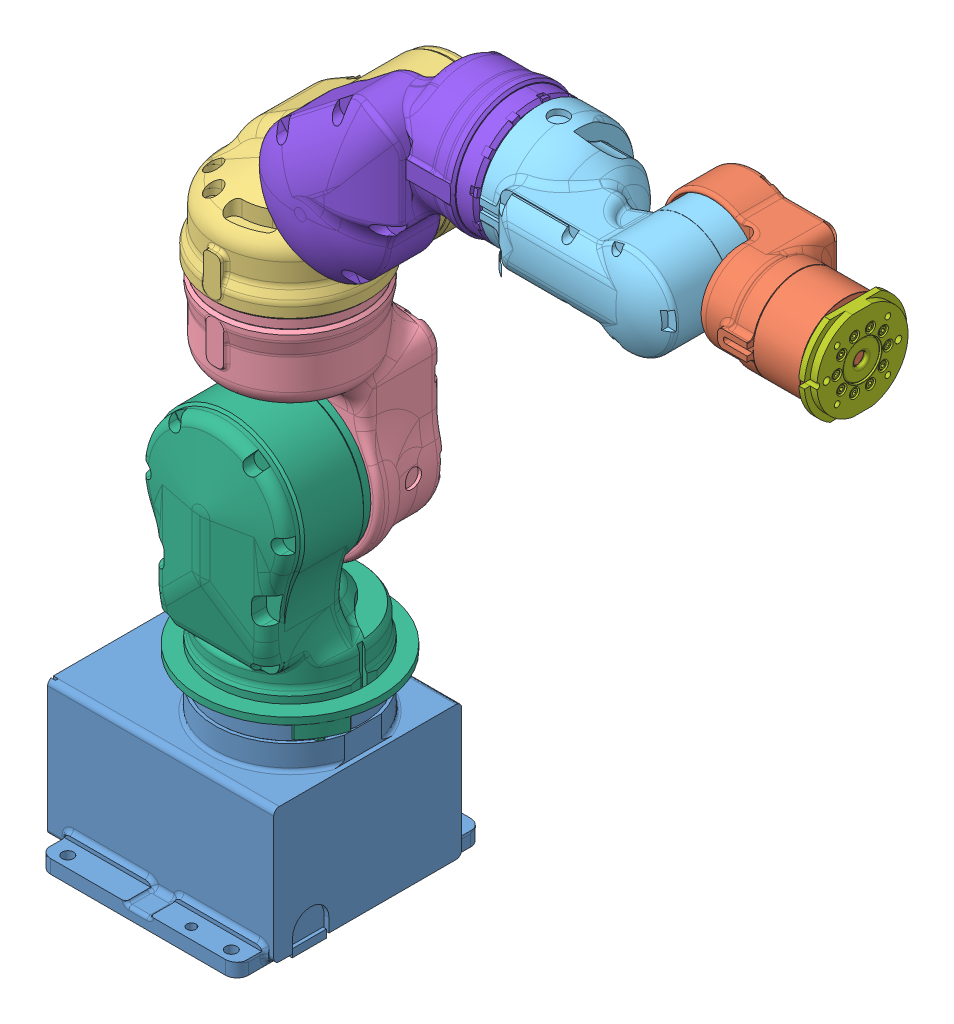
SolidWorks assembly SIA5, configuration ﾃﾞﾌｫﾙﾄ. Lengths in mm.
Overall size (649.6 695.94 220.28).
8 component instances, 8 part files, 16 mates.
Components (placement in the parent):
- base_link-1: base_link [ﾃﾞﾌｫﾙﾄ] at (7.849 -82.5515 222.6419) size (215.3 168.54 220.28)
- link_b-1: link_b [ﾃﾞﾌｫﾙﾄ] at (7.849 -82.5515 222.6419) size (184.27 91.84 114.81)
- link_e-1: link_e [ﾃﾞﾌｫﾙﾄ] at (7.849 -82.5515 222.6419) size (210.08 168.26 150.76)
- link_l-1: link_l [ﾃﾞﾌｫﾙﾄ] at (7.849 -82.5515 222.6419) size (157.25 229.06 145.97)
- link_r-1: link_r [ﾃﾞﾌｫﾙﾄ] at (7.849 -82.5515 222.6419) size (176 105.65 121.5)
- link_s-1: link_s [ﾃﾞﾌｫﾙﾄ] at (7.849 -82.5515 222.6419) size (160 226 160)
- link_t-1: link_t [ﾃﾞﾌｫﾙﾄ] at (7.349 -82.5515 222.6419) size (11 78 89.93)
- link_u-1: link_u [ﾃﾞﾌｫﾙﾄ] at (7.849 -82.5515 222.6419) size (192.08 173.27 131.93)
Mates (geometry in assembly coordinates):
- 一致3: coincident anti-aligned: plane of base_link-1 through (7.849 84.9485 222.6419) normal (0 1 0); plane of link_s-1 through (7.849 84.9485 222.6419) normal (0 -1 0)
- 同心円2: concentric anti-aligned: cylinder of base_link-1 through (7.849 84.9485 222.6419) axis (0 -1 0) radius 55; cylinder of link_s-1 through (7.849 84.9485 222.6419) axis (0 1 0) radius 80
- 一致4: coincident anti-aligned: plane of link_l-1 through (72.349 226.9485 203.1419) normal (0 0 1); plane of link_s-1 through (7.849 281.9485 203.1419) normal (0 0 -1)
- 同心円3: concentric aligned: cylinder of link_l-1 through (7.849 226.9485 203.1419) axis (0 0 1) radius 64.5; cylinder of link_s-1 through (7.849 226.9485 204.1419) axis (0 0 1) radius 63.5
- 一致5: coincident anti-aligned: plane of link_e-1 through (75.147 383.9485 289.9399) normal (0 -1 0); plane of link_l-1 through (7.849 383.9485 222.6419) normal (0 1 0)
- 一致6: coincident anti-aligned: plane of link_e-1 through (53.8779 519.4485 239.6419) normal (0 0 1); plane of link_u-1 through (38.707 442.8065 239.6419) normal (0 0 -1)
- 一致7: coincident anti-aligned: plane of link_r-1 through (226.849 -141.5336 195.6172) normal (-1 0 0); plane of link_u-1 through (226.849 564.7627 266.9583) normal (1 0 0)
- 一致10: coincident anti-aligned: plane of link_b-1 through (362.849 -141.5336 158.4172) normal (0 0 1); plane of link_r-1 through (362.849 -141.5336 158.4172) normal (0 0 -1)
- 同心円6: concentric anti-aligned: cylinder of link_b-1 through (362.849 -141.5336 180.6172) axis (0 0 1) radius 41.5; cylinder of link_r-1 through (362.849 -141.5336 204.1172) axis (0 0 -1) radius 40
- 一致11: coincident anti-aligned: plane of link_b-1 through (499.349 -141.5336 195.6172) normal (1 0 0); plane of link_t-1 through (499.349 -141.5336 195.6172) normal (-1 0 0)
- 同心円7: concentric aligned: cylinder of link_b-1 through (499.349 -141.5336 195.6172) axis (-1 0 0) radius 33.75; cylinder of link_t-1 through (499.349 -141.5336 195.6172) axis (-1 0 0) radius 27.5
- 同心円10: concentric aligned: cylinder of link_e-1 through (7.849 393.9485 222.6419) axis (0 -1 0) radius 38.822; cylinder of link_l-1 through (7.849 383.9485 222.6419) axis (0 -1 0) radius 63.5
- 一致13: coincident anti-aligned: plane of link_e-1 through (53.8779 519.4485 239.6419) normal (0 0 1); plane of link_u-1 through (38.707 442.8065 239.6419) normal (0 0 -1)
- 同心円11: concentric anti-aligned: cylinder of link_e-1 through (92.849 496.9485 234.6419) axis (0 0 1) radius 27.7332; cylinder of link_u-1 through (92.849 496.9485 245.6419) axis (0 0 -1) radius 32.0458
- 一致14: coincident anti-aligned: plane of link_r-1 through (226.849 556.9485 222.6419) normal (-1 0 0); plane of link_u-1 through (226.849 564.7627 266.9583) normal (1 0 0)
- 同心円12: concentric aligned: cylinder of link_r-1 through (222.249 556.9485 222.6419) axis (1 0 0) radius 52.5; cylinder of link_u-1 through (221.849 556.9485 222.6419) axis (1 0 0) radius 30.7597
